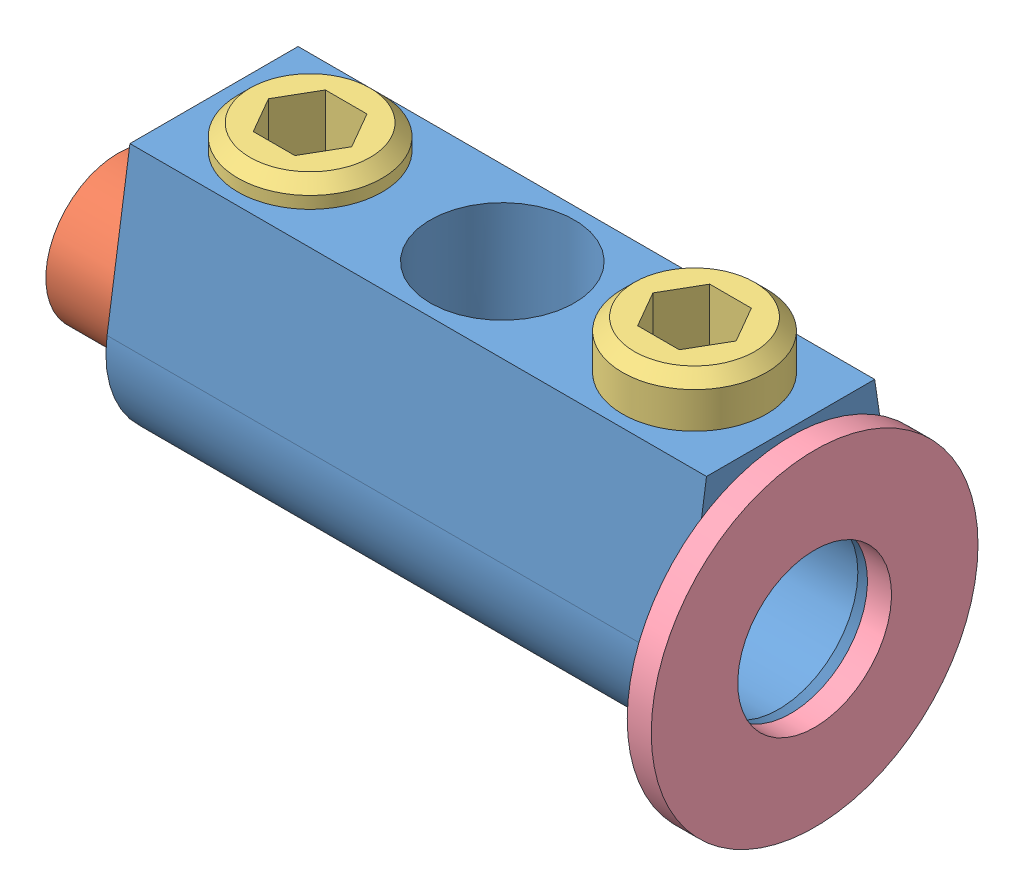
SolidWorks assembly BellcrankLock, configuration Default. Lengths in mm.
Overall size (14.5 8.25 7.4).
5 component instances, 4 part files, 8 mates.
Components (placement in the parent):
- Kronmuffe-1: Kronmuffe [Default] at origin size (12 5.8 4.5)
- BrassTube2-1: BrassTube2 [Default] x (0 0 -1) z (0 1 0) size (3 8 3)
- M3-3-set-1: M3-3-set [Default] at (-4 1.05 0) size (3 3 3)
- M3-3-set-2: M3-3-set [Default] at (4 1.55 0) size (3 3 3)
- M3-washer-1: M3-washer [Default] at (6.5 0 0) x (0 0.9957 0.092639) z (0 -0.092639 0.9957) size (6.8 0.5 6.8)
Mates (geometry in assembly coordinates):
- Concentric1: concentric anti-aligned: cylinder of Kronmuffe-1; cylinder of BrassTube2-1
- Concentric2: concentric aligned: cylinder of Kronmuffe-1; cylinder of BrassTube2-1
- Concentric3: concentric anti-aligned: cylinder of Kronmuffe-1; cylinder of M3-washer-1
- Coincident1: coincident anti-aligned: plane of Kronmuffe-1 through (6 0 0) normal (1 0 0); plane of M3-washer-1
- Concentric4: concentric aligned: cylinder of Kronmuffe-1; cylinder of M3-3-set-1
- Concentric5: concentric aligned: cylinder of Kronmuffe-1; cylinder of M3-3-set-2
- Distance1: distance = 0.5 mm aligned: plane of Kronmuffe-1; plane of M3-3-set-1
- Distance2: distance = 1 mm aligned: plane of Kronmuffe-1; plane of M3-3-set-2
